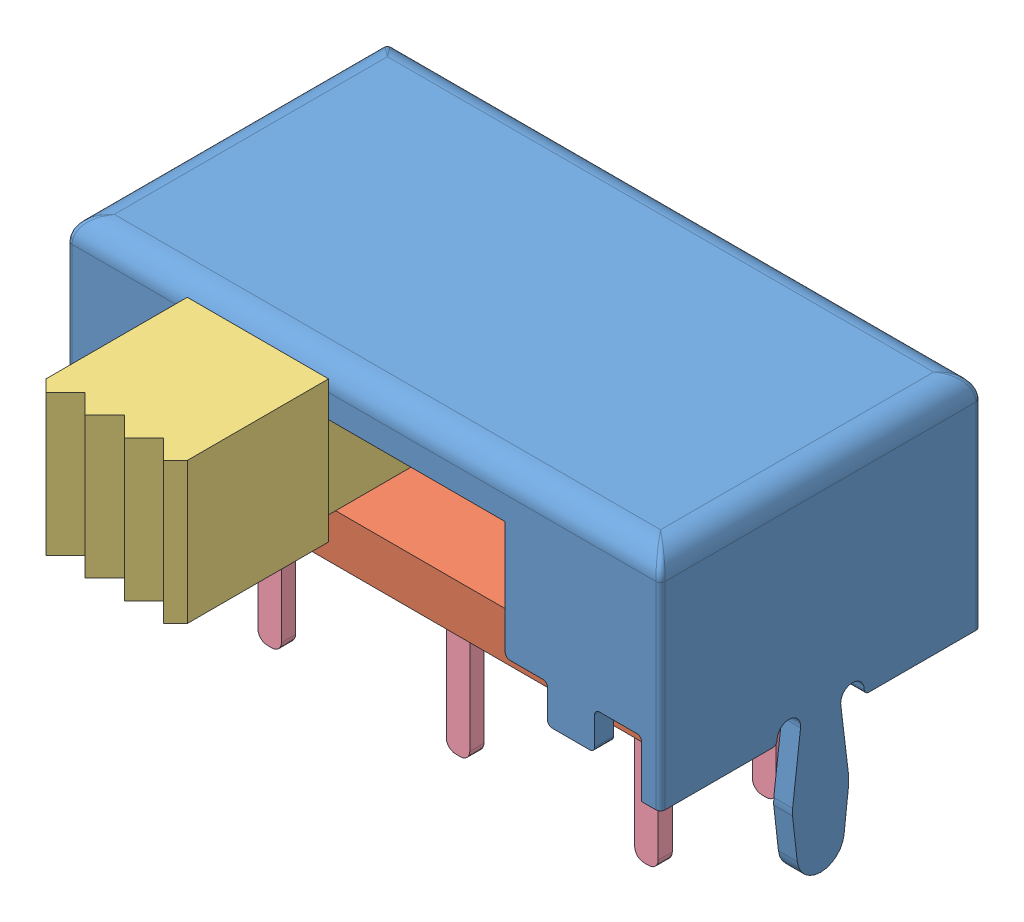
SolidWorks assembly EG2215, configuration Domyślna. Lengths in mm.
Overall size (12.6 7.8 10.3).
4 component instances, 4 part files, 15 mates.
Components (placement in the parent):
- Body^EG2215-1: Body^EG2215 [Domyślna] at origin size (12.6 7.5 6.8) (virtual)
- Insert^EG2215-1: Insert^EG2215 [Domyślna] at (0 0 -3) size (11.8 3.6 6) (virtual)
- Slider^EG2215-2: Slider^EG2215 [Domyślna] at (0 0 -3) size (3 3 9.9) (virtual)
- Pins^EG2215-1: Pins^EG2215 [Domyślna] at origin size (8.5 3.8 2.8) (virtual)
Mates (geometry in assembly coordinates):
- InPlace1: in place: plane of ? through (0 0 0) normal (0 0 1); moOrthogonalPlaneRef_w of ? through (0 0 0) normal (0 1 0); plane of ? through (0 0 0) normal (1 0 0); unknown of ?
- Coincident1: coincident aligned: 
- Coincident2: coincident aligned: plane of Reference^EG2215-1 through (0 0 0) normal (0 1 0)
- Coincident3: coincident anti-aligned: plane of Reference^EG2215-1 through (0 0 0) normal (1 0 0)
- InPlace2: in place: plane of ? through (0 0 -3) normal (0 0 1); plane of ? through (0 0 -3) normal (0 0 1); plane of ? through (0 0 -3) normal (0 0 1); plane of ? through (0 0 -3) normal (0 1 0); plane of ? through (0 0 -3) normal (0 0 1); plane of ? through (0 0 -3) normal (1 0 0); plane of ? through (0 0 -3) normal (0 0 1); unknown of ?
- Coincident1: coincident aligned: plane of ?; plane of ?
- Coincident2: coincident aligned: moOrthogonalPlaneRef_w of Body^EG2215-1 through (0 0 -3) normal (0 1 0); plane of Part1^EG2215-1 through (0 0 -3) normal (0 1 0)
- Coincident3: coincident anti-aligned: moOrthogonalPlaneRef_w of Body^EG2215-1 through (0 0 -3) normal (-1 0 0); plane of Part1^EG2215-1 through (0 0 -3) normal (1 0 0)
- Coincident8: coincident anti-aligned: plane of Body^EG2215-1 through (0 0 -3) normal (0 0 1); plane of Slider^EG2215-2 through (0 0 -3) normal (0 0 -1)
- Coincident9: coincident anti-aligned: plane of Body^EG2215-1 through (-3 2.75 -3.401) normal (0 -1 0); plane of Slider^EG2215-2 through (-3 2.75 6.7284) normal (0 1 0)
- Width1: width anti-aligned: plane of Body^EG2215-1 through (-3 0.25 -3.401) normal (1 0 0); plane of Slider^EG2215-2 through (3 2.75 -3.401) normal (-1 0 0); plane of Body^EG2215-1 through (-3 2.75 6.7284) normal (-1 0 0); plane of Slider^EG2215-2 through (-1 2.75 6.7284) normal (1 0 0)
- InPlace4: in place: plane of ? through (0 0 0) normal (0 0 1); plane of ? through (0 0 0) normal (0 1 0); plane of ? through (0 0 0) normal (1 0 0); unknown of ?
- Coincident10: coincident aligned: 
- Coincident11: coincident aligned: plane of Pins^EG2215-1 through (0 0 0) normal (0 1 0)
- Coincident12: coincident anti-aligned: plane of Pins^EG2215-1 through (0 0 0) normal (1 0 0)
